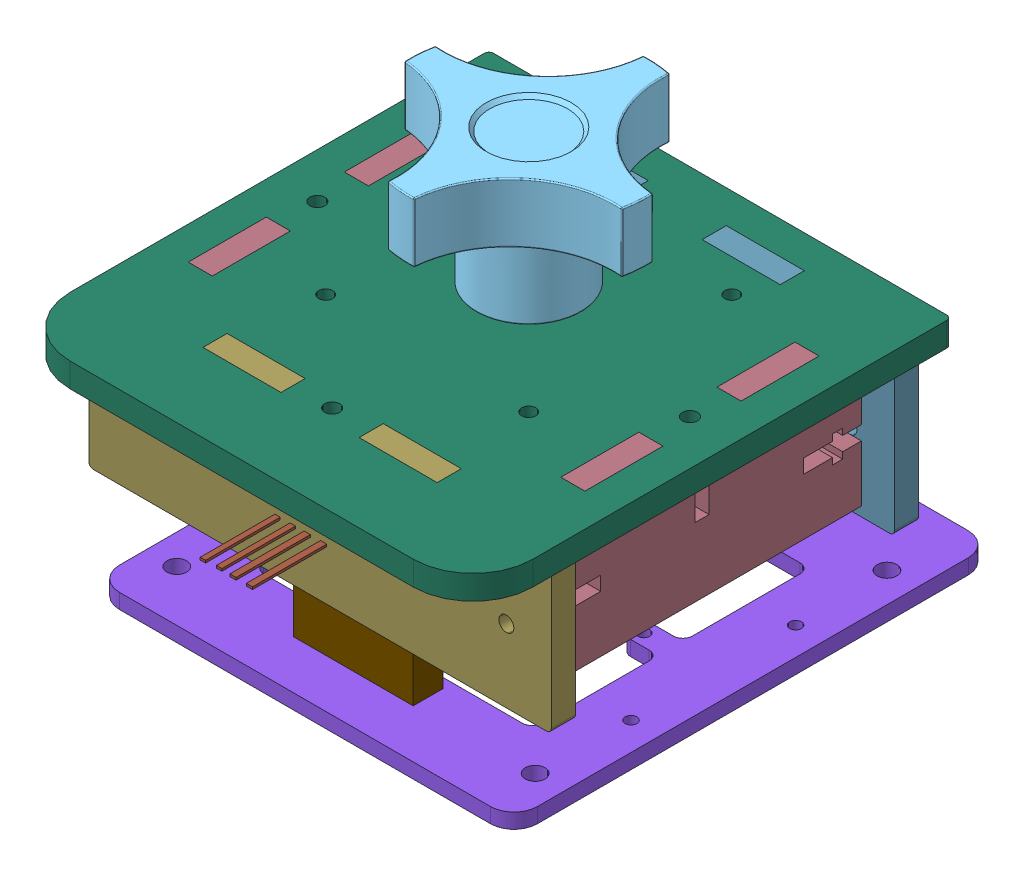
SolidWorks assembly New hinged lid, configuration Default. Lengths in mm.
Overall size (98.36 87.94 115.03).
43 component instances, 23 part files, 83 mates.
Components (placement in the parent):
- Hinge-1: Hinge [Default] at (70.0982 -3.9311 -32.9531) x (-1 0 -0.00001) z (0 -1 -0.000186) size (43.09 12.7 36.52) (hidden)
- Hinge-2: Hinge [Default] at (-25.8646 -55.4891 -84.4606) x (1 0 0.00001) z (-0.00001 0 1) size (43.09 12.7 36.52)
- Hinge bracket-1: Hinge bracket [Default] at (23.7148 -45.0072 -57.9232) x (-0.00001 0 1) z (-1 0 -0.00001) size (19.05 15.24 42.86)
- Heated bracket-1: Heated bracket [Default] at (29.9601 -15.1388 -28.7536) x (1 0 0.00001) z (-0.00001 0.000244 1) size (69.85 3.17 41.91)
- Plate-1: Plate [Default] at (40.7551 -19.901 -27.7973) x (1 0 0.00001) z (-0.00001 0.000244 1) size (48.26 1.59 40)
- compresed spring  9657K81-1: compresed spring  9657K81 [Default] at (-6.4585 -16.615 -30.525) x (0.523814 -0.009189 -0.851783) z (0.851833 0.005651 0.523784) size (5.56 9.65 5.56) (hidden)
- compresed spring  9657K81-3: compresed spring  9657K81 [Default] at (-7.0933 -15.1175 -46.5641) x (-0.445855 -0.000219 -0.895105) z (-0.895105 0.000109 0.445855) size (5.56 9.65 5.56)
- 1-8 in spacer-2: 1-8 in spacer [Default] at (43.7064 -18.3099 -12.9078) x (0.998444 -0.000014 -0.055766) z (0.055766 0.000244 0.998444) size (4.76 3.17 4.76)
- 1-8 in spacer-1: 1-8 in spacer [Default] at (43.7067 -18.3183 -47.1978) x (0.999061 0.000011 0.043334) z (-0.043334 0.000244 0.999061) size (4.76 3.17 4.76)
- 1-8 in spacer-3: 1-8 in spacer [Default] at (0.5267 -18.3183 -47.1982) x (0.966016 -0.000063 -0.258481) z (0.258481 0.000236 0.966016) size (4.76 3.17 4.76) (hidden)
- 1-8 in spacer-4: 1-8 in spacer [Default] at (0.5264 -18.3099 -12.9083) x (0.632801 -0.000189 -0.774315) z (0.774315 0.000155 0.632801) size (4.76 3.17 4.76)
- Lid bracket-1: Lid bracket [Default] at (57.0412 6.5511 5.8182) x (-0.00001 0.000244 1) z (-1 0 -0.00001) size (57.15 29.21 69.85)
- Mounting plate-1: Mounting plate [Default] at (3.5426 -48.1822 -13.4051) size (88.9 3.17 101.6)
- M3_8mm_SS_screw_91292A112-1: M3_8mm_SS_screw_91292A112 [91292A112] at (0.5267 -11.9058 -47.1998) x (0.999971 0.000002 0.007564) z (0 1 -0.000244) size (5.5 5.5 11.58)
- M3_8mm_SS_screw_91292A112-2: M3_8mm_SS_screw_91292A112 [91292A112] at (0.5264 -11.8974 -12.9098) x (0.999971 0.000002 0.007564) z (0 1 -0.000244) size (5.5 5.5 11.58)
- M3_8mm_SS_screw_91292A112-3: M3_8mm_SS_screw_91292A112 [91292A112] at (43.7067 -11.9058 -47.1994) x (0.999971 0.000002 0.007564) z (0 1 -0.000244) size (5.5 5.5 11.58)
- M3_8mm_SS_screw_91292A112-4: M3_8mm_SS_screw_91292A112 [91292A112] at (43.7064 -11.8974 -12.9094) x (0.999971 0.000002 0.007564) z (0 1 -0.000244) size (5.5 5.5 11.58)
- 3-4in-shoulder screw 3-16 dia-1: 3-4in-shoulder screw 3-16 dia [95446A360] at (-7.0933 -24.7938 -46.5617) x (0.905744 -0.000104 -0.423825) z (-0.423825 -0.000221 -0.905744) size (7.94 28.12 7.94)
- 3-4in-shoulder screw 3-16 dia-2: 3-4in-shoulder screw 3-16 dia [95446A360] at (51.3264 -24.7857 -13.5412) x (0.940326 0.000083 0.340275) z (0.340275 -0.00023 -0.940326) size (7.94 28.12 7.94)
- 3-4in-shoulder screw 3-16 dia-3: 3-4in-shoulder screw 3-16 dia [95446A360] at (-7.0936 -24.7857 -13.5417) x (0.940326 0.000083 0.340275) z (0.340275 -0.00023 -0.940326) size (7.94 28.12 7.94)
- 3-4in-shoulder screw 3-16 dia-4: 3-4in-shoulder screw 3-16 dia [95446A360] at (51.3267 -24.7938 -46.5612) x (0.992625 0.00003 0.121222) z (0.121222 -0.000242 -0.992625) size (7.94 28.12 7.94)
- Kapton Heater-1: Kapton Heater [Default] at (26.8423 -18.319 -50.039) x (0.00001 -0.000244 -1) z (1 0 0.00001) size (79.75 1 35)
- Lid_front_wood-1: Lid_front_wood [Default] at (27.0323 -16.8764 9.1767) x (1 0 0.00001) z (-0.00001 0.000244 1) size (98.36 34.13 5.13)
- Lid_side_wood-1: Lid_side_wood [Default] at (59.1667 -23.1699 -43.3132) x (1 0 0.00001) z (-0.00001 0.000244 1) size (5.13 32.13 67.82)
- Lid_side_wood-2: Lid_side_wood [Default] at (-20.0633 -23.1699 -43.314) x (1 0 0.00001) z (-0.00001 0.000244 1) size (5.13 32.13 67.82)
- Lid_back_wood-1: Lid_back_wood [Default] at (14.808 -29.7535 -58.6303) x (-1 0 -0.00001) z (0.00001 -0.000244 -1) size (98.36 34.13 5.13)
- Lid_top_wood-1: Lid_top_wood [Default] at (55.5466 0.6138 -15.6234) x (1 0 0.00001) z (-0.00001 0.000244 1) size (98.36 5.13 101.72)
- M3_8mm_SS_screw_91292A112-5: M3_8mm_SS_screw_91292A112 [91292A112] at (44.4304 -2.0428 15.0076) x (0.999989 -0.004771 0.000006) z (-0.004771 -0.999988 0.001283) size (5.5 5.5 11.58) (suppressed, hidden)
- M3_8mm_SS_screw_91292A112-6: M3_8mm_SS_screw_91292A112 [91292A112] at (44.4304 -2.0941 -24.9924) x (0.999989 -0.004771 0.000006) z (-0.004771 -0.999988 0.001283) size (5.5 5.5 11.58) (suppressed, hidden)
- M3_8mm_SS_screw_91292A112-7: M3_8mm_SS_screw_91292A112 [91292A112] at (-2.3818 -1.8411 -1.9191) x (0.999989 -0.004771 0.000006) z (-0.004771 -0.999988 0.001283) size (5.5 5.5 11.58) (suppressed, hidden)
- M3_8mm_SS_screw_91292A112-8: M3_8mm_SS_screw_91292A112 [91292A112] at (-5.5685 -1.8555 -24.9927) x (0.999989 -0.004771 0.000006) z (-0.004771 -0.999988 0.001283) size (5.5 5.5 11.58) (suppressed, hidden)
- Hinge1-1: Hinge1 [Default] at (27.453 -24.3489 -71.4953) x (-1 0 -0.00001) z (0.00001 0 -1) (suppressed, hidden)
- 5-16in-phlps-black-91249A190-6: 5-16in-phlps-black-91249A190 [91249A190] at (37.9918 -10.3177 -54.6611) x (-1 0 -0.00001) z (0.00001 -0.000244 -1) size (8.18 8.18 10.99)
- 1in-8-32-phlp-91249A201-1: 1in-8-32-phlp-91249A201 [91249A201] at (37.992 -51.1985 -78.0736) x (-0.619923 0 0.784662) z (0 1 0) size (8.18 8.18 28.47)
- 1in-8-32-phlp-91249A201-2: 1in-8-32-phlp-91249A201 [91249A201] at (6.242 -51.1985 -78.0739) x (-0.837169 0 -0.546944) z (0 1 0) size (8.18 8.18 28.47)
- 5-16in-phlps-black-91249A190-7: 5-16in-phlps-black-91249A190 [91249A190] at (6.2418 -10.3177 -54.6614) x (-1 0 -0.00001) z (0.00001 -0.000244 -1) size (8.18 8.18 10.99)
- latch_bracket_2-1: latch_bracket_2 [Default] at (43.6698 -45.0072 13.4302) size (25.4 15.24 6.35)
- latch_2-1: latch_2 [Default] at (43.8409 -12.4473 -1.4793) x (1 -0.000024 0.00001) z (-0.000024 -1 0.000244) size (42.86 9.42 7.94)
- strike_1-1: strike_1 [Default] at (22.836 -29.6346 7.4002) x (-0.000088 0 -1) z (1 0 -0.000088) size (6.75 9.4 25)
- 3-4in-6-32-phlp-undercut-91099A224-1: 3-4in-6-32-phlp-undercut-91099A224 [91099A224] at (14.5756 -29.7616 4.0262) x (1 0 0) z (0 1 0) size (6.65 6.65 19.05)
- 3-4in-6-32-phlp-undercut-91099A224-3: 3-4in-6-32-phlp-undercut-91099A224 [91099A224] at (29.6568 -29.7616 4.0262) x (1 0 0) z (0 1 0) size (6.65 6.65 19.05)
- 1.4inbolt-1: 1.4inbolt [92240A430] at (22.1165 -11.6784 -30.0547) x (0.999158 0.00001 0.041024) z (0 -1 0.000244) size (13.41 13.11 36.14)
- Bolt with knob-1: Bolt with knob [5993K44] at (22.1165 15.9441 -30.0614) x (0.996738 0.00002 0.0807) z (0 1 -0.000244) size (50.8 61.06 29.44)
Mates (geometry in assembly coordinates):
- Concentric38: concentric aligned: circle of Plate-1; circle of 1-8 in spacer-2
- Concentric39: concentric aligned: circle of Plate-1; circle of 1-8 in spacer-4
- Concentric40: concentric aligned: circle of Plate-1; circle of 1-8 in spacer-3
- Coincident53: coincident anti-aligned: plane of Heated bracket-1 through (-12.8087 -15.134 -9.0992) normal (0 -1 0.000244); circle of 1-8 in spacer-4
- Coincident54: coincident anti-aligned: plane of Heated bracket-1 through (-12.8087 -15.134 -9.0992) normal (0 -1 0.000244); circle of 1-8 in spacer-1
- Concentric42: concentric aligned: circle of Plate-1; circle of 1-8 in spacer-1
- Coincident55: coincident anti-aligned: plane of Heated bracket-1 through (-12.8087 -15.134 -9.0992) normal (0 -1 0.000244); plane of 1-8 in spacer-2 through (43.7064 -15.1349 -12.9086) normal (0 1 -0.000244)
- Coincident56: coincident anti-aligned: plane of Heated bracket-1 through (-12.8087 -15.134 -9.0992) normal (0 -1 0.000244); circle of 1-8 in spacer-3
- Coincident80: coincident anti-aligned: plane of Hinge bracket-1 through (43.5483 -45.0072 -83.6616) normal (0 -1 0); plane of Mounting plate-1 through (61.567 -45.0072 -79.0734) normal (0 1 0)
- Concentric43: concentric anti-aligned: circle of Hinge bracket-1; circle of Mounting plate-1
- Coincident91: coincident anti-aligned: plane of Plate-1 through (-2.0137 -18.3092 -10.0533) normal (0 1 -0.000244); plane of 1-8 in spacer-1 through (43.7067 -18.3183 -47.1978) normal (0 -1 0.000244)
- Concentric56: concentric aligned: circle of 1-8 in spacer-3; circle of M3_8mm_SS_screw_91292A112-1
- Concentric57: concentric aligned: circle of Plate-1; circle of M3_8mm_SS_screw_91292A112-1
- Concentric58: concentric anti-aligned: circle of Heated bracket-1; circle of M3_8mm_SS_screw_91292A112-1
- Coincident94: coincident anti-aligned: plane of Plate-1 through (-2.0137 -19.8967 -10.0529) normal (0 -1 0.000244); plane of M3_8mm_SS_screw_91292A112-1 through (0.5267 -19.9058 -47.1979) normal (0 1 -0.000244)
- Concentric60: concentric aligned: circle of 1-8 in spacer-4; circle of M3_8mm_SS_screw_91292A112-2
- Concentric61: concentric aligned: circle of Heated bracket-1; circle of M3_8mm_SS_screw_91292A112-2
- Concentric64: concentric aligned: circle of Plate-1; circle of M3_8mm_SS_screw_91292A112-3
- Concentric65: concentric aligned: circle of Plate-1; circle of M3_8mm_SS_screw_91292A112-4
- Coincident98: coincident anti-aligned: plane of Plate-1 through (-2.0137 -19.8967 -10.0529) normal (0 -1 0.000244); plane of M3_8mm_SS_screw_91292A112-4 through (43.7064 -19.8974 -12.9074) normal (0 1 -0.000244)
- Coincident99: coincident anti-aligned: plane of Plate-1 through (-2.0137 -19.8967 -10.0529) normal (0 -1 0.000244); plane of M3_8mm_SS_screw_91292A112-3 through (43.7067 -19.9058 -47.1974) normal (0 1 -0.000244)
- Coincident100: coincident anti-aligned: plane of Plate-1 through (-2.0137 -19.8967 -10.0529) normal (0 -1 0.000244); plane of M3_8mm_SS_screw_91292A112-2 through (0.5264 -19.8974 -12.9079) normal (0 1 -0.000244)
- Concentric67: concentric anti-aligned: line of Hinge bracket-1 through (37.992 -21.6195 -78.0736) axis (0 -1 0); circle of Mounting plate-1
- Concentric70: concentric anti-aligned: circle of 3-4in-shoulder screw 3-16 dia-2; circle of Lid bracket-1
- Coincident102: coincident anti-aligned: plane of Lid bracket-1 through (-12.8083 -5.7449 -51.0114) normal (0 -1 0.000244); plane of 3-4in-shoulder screw 3-16 dia-2 through (51.3264 -5.7357 -13.5458) normal (0 1 -0.000244)
- Concentric71: concentric anti-aligned: cylinder of 3-4in-shoulder screw 3-16 dia-2 through (51.3264 -5.7357 -13.5458) axis (0 -1 0.000244) radius 2.3813; circle of Heated bracket-1
- Coincident105: coincident aligned: line of Plate-1 through (-2.0137 -18.3092 -10.0533) axis (1 0 0.00001); line of Kapton Heater-1 through (4.825 -18.3092 -10.0532) axis (1 0 0.00001)
- Parallel1: parallel aligned: line of Plate-1 through (-2.0133 -18.319 -50.0533) axis (-0.00001 0.000244 1); line of Kapton Heater-1 through (4.8253 -17.8188 -49.5533) axis (-0.00001 0.000244 1)
- Concentric74: concentric anti-aligned: circle of Mounting plate-1; circle of Hinge-2
- Concentric75: concentric aligned: circle of Mounting plate-1; circle of Hinge-2
- Coincident114: coincident anti-aligned: plane of Hinge bracket-1 through (43.5483 -29.7672 -83.6616) normal (0 1 0); plane of Hinge-2 through (43.8546 -29.7672 -83.9231) normal (0 -1 0)
- Coincident155: coincident anti-aligned: plane of Lid bracket-1 through (-12.8083 -5.7449 -51.0114) normal (0 -1 0.000244); plane of 3-4in-shoulder screw 3-16 dia-1 through (-7.0933 -5.7438 -46.5664) normal (0 1 -0.000244)
- Concentric89: concentric anti-aligned: circle of compresed spring  9657K81-3; circle of 3-4in-shoulder screw 3-16 dia-1
- Coincident166: coincident anti-aligned: plane of Hinge bracket-1 through (43.5483 -29.7672 -83.6616) normal (0 1 0); plane of ? through (44.3421 -29.7672 -85.7726) normal (0 -1 0)
- Coincident168: coincident anti-aligned: plane of Lid bracket-1 through (-12.8082 0.6033 -58.633) normal (0.00001 -0.000244 -1); plane of ? through (-0.1082 -2.6196 -58.6321) normal (-0.00001 0.000244 1)
- Coincident174: coincident anti-aligned: plane of ? through (44.3418 -16.3661 -62.5971) normal (0.00001 -0.000244 -1); plane of 5-16in-phlps-black-91249A190-6 through (37.9918 -10.3197 -62.5986) normal (-0.00001 0.000244 1)
- Coincident175: coincident anti-aligned: plane of ? through (44.3418 -16.3661 -62.5971) normal (0.00001 -0.000244 -1); plane of 5-16in-phlps-black-91249A190-6 through (37.9918 -10.3197 -62.5986) normal (-0.00001 0.000244 1)
- Concentric104: concentric anti-aligned: circle of Mounting plate-1; circle of ?
- Concentric107: concentric anti-aligned: circle of Mounting plate-1; circle of ?
- Concentric108: concentric anti-aligned: circle of ?; circle of 1in-8-32-phlp-91249A201-1
- Concentric109: concentric anti-aligned: circle of ?; circle of 1in-8-32-phlp-91249A201-2
- Coincident177: coincident anti-aligned: plane of ? through (-0.1081 -25.7985 -72.0276) normal (0 1 0); plane of 1in-8-32-phlp-91249A201-1 through (37.992 -25.7985 -78.0736) normal (0 -1 0)
- Coincident178: coincident anti-aligned: plane of ? through (-0.1081 -25.7985 -72.0276) normal (0 1 0); plane of 1in-8-32-phlp-91249A201-2 through (6.242 -25.7985 -78.0739) normal (0 -1 0)
- Concentric110: concentric aligned: circle of Mounting plate-1; circle of latch_bracket_2-1
- Concentric111: concentric aligned: circle of Mounting plate-1; circle of latch_bracket_2-1
- Coincident179: coincident anti-aligned: plane of Mounting plate-1 through (61.567 -45.0072 -79.0734) normal (0 1 0); plane of latch_bracket_2-1 through (9.4162 -45.0072 7.2012) normal (0 -1 0)
- Concentric112: concentric aligned: circle of latch_bracket_2-1; circle of strike_1-1
- Concentric113: concentric aligned: circle of latch_bracket_2-1; circle of strike_1-1
- Coincident180: coincident anti-aligned: plane of latch_bracket_2-1 through (9.4162 -29.7672 7.2012) normal (0 1 0); plane of strike_1-1 through (34.6175 -29.7672 0.6523) normal (0 -1 0)
- Coincident181: coincident anti-aligned: plane of Lid bracket-1 through (-12.8088 -28.5928 -1.4759) normal (-0.00001 0.000244 1); plane of latch_2-1 through (0.6849 -27.7346 -1.4759) normal (0.00001 -0.000244 -1)
- Concentric114: concentric aligned: circle of Lid bracket-1; circle of latch_2-1
- Concentric115: concentric aligned: circle of Lid bracket-1; circle of latch_2-1
- Concentric116: concentric anti-aligned: circle of Lid bracket-1; circle of 3-4in-shoulder screw 3-16 dia-1
- Concentric117: concentric anti-aligned: circle of Heated bracket-1; cylinder of 3-4in-shoulder screw 3-16 dia-1 through (-7.0933 -5.7438 -46.5664) axis (0 -1 0.000244) radius 2.3813
- Concentric118: concentric anti-aligned: circle of Lid bracket-1; circle of 3-4in-shoulder screw 3-16 dia-4
- Concentric119: concentric anti-aligned: circle of Heated bracket-1; cylinder of 3-4in-shoulder screw 3-16 dia-4 through (51.3267 -5.7438 -46.5658) axis (0 -1 0.000244) radius 2.3813
- Coincident182: coincident anti-aligned: plane of Lid bracket-1 through (-12.8083 -5.7449 -51.0114) normal (0 -1 0.000244); plane of 3-4in-shoulder screw 3-16 dia-4 through (51.3267 -5.7438 -46.5658) normal (0 1 -0.000244)
- Concentric120: concentric anti-aligned: circle of Heated bracket-1; cylinder of 3-4in-shoulder screw 3-16 dia-3 through (-7.0936 -5.7357 -13.5464) axis (0 -1 0.000244) radius 2.3813
- Concentric121: concentric aligned: circle of Lid bracket-1; cylinder of 3-4in-shoulder screw 3-16 dia-3 through (-7.0936 -5.7357 -13.5464) axis (0 -1 0.000244) radius 2.3813
- Coincident183: coincident anti-aligned: plane of Lid bracket-1 through (-12.8083 -5.7449 -51.0114) normal (0 -1 0.000244); plane of 3-4in-shoulder screw 3-16 dia-3 through (-7.0936 -5.7357 -13.5464) normal (0 1 -0.000244)
- Concentric123: concentric anti-aligned: circle of Lid bracket-1; circle of ?
- Concentric124: concentric anti-aligned: circle of Lid bracket-1; circle of ?
- Concentric125: concentric anti-aligned: circle of ?; circle of 5-16in-phlps-black-91249A190-6
- Concentric133: concentric anti-aligned: circle of strike_1-1; circle of 3-4in-6-32-phlp-undercut-91099A224-1
- Concentric134: concentric aligned: circle of strike_1-1; circle of 3-4in-6-32-phlp-undercut-91099A224-3
- Coincident186: coincident aligned: cone of strike_1-1 through (14.5756 -28.0146 4.0262) axis (0 -1 0); cone of 3-4in-6-32-phlp-undercut-91099A224-1 through (14.5756 -28.263 4.0262) axis (0 -1 0)
- Coincident187: coincident aligned: cone of strike_1-1 through (29.6568 -28.0146 4.0262) axis (0 -1 0); cone of 3-4in-6-32-phlp-undercut-91099A224-3 through (29.6568 -28.263 4.0262) axis (0 -1 0)
- Coincident188: coincident anti-aligned: plane of Lid bracket-1 through (-12.8088 0.6172 -1.483) normal (0 1 -0.000244); plane of Lid_top_wood-1 through (58.5961 0.6221 18.254) normal (0 -1 0.000244)
- Concentric135: concentric aligned: circle of Lid bracket-1; circle of 1.4inbolt-1
- Concentric136: concentric aligned: circle of 1.4inbolt-1; circle of Bolt with knob-1
- Coincident189: coincident anti-aligned: plane of 1.4inbolt-1 through (22.1165 23.8816 -30.0633) normal (0 1 -0.000244); plane of Bolt with knob-1 through (22.1165 23.8816 -30.0633) normal (0 -1 0.000244)
- Concentric137: concentric aligned: circle of Lid bracket-1; circle of Lid_top_wood-1
- Concentric138: concentric aligned: circle of Lid bracket-1; circle of Lid_top_wood-1
- Coincident191: coincident aligned: line of Lid_back_wood-1 through (-2.7832 5.7333 -58.6392) axis (1 0 0.00001); line of Lid_top_wood-1 through (-2.7832 5.7333 -58.6392) axis (1 0 0.00001)
- Coincident192: coincident aligned: line of Lid_back_wood-1 through (13.8168 5.7333 -58.639) axis (0.00001 -0.000244 -1); line of Lid_top_wood-1 through (13.8168 5.7333 -58.639) axis (0.00001 -0.000244 -1)
- Coincident193: coincident aligned: line of Lid_side_wood-2 through (-20.0633 5.7355 -49.6343) axis (-0.00001 0.000244 1); line of Lid_top_wood-1 through (-20.0633 5.7355 -49.6343) axis (-0.00001 0.000244 1)
- Coincident194: coincident aligned: line of Lid_side_wood-2 through (-14.9333 5.7355 -49.6343) axis (-1 0 -0.00001); line of Lid_top_wood-1 through (-14.9333 5.7355 -49.6343) axis (-1 0 -0.00001)
- Coincident195: coincident aligned: line of Lid_side_wood-1 through (59.1667 5.7355 -49.6336) axis (-0.00001 0.000244 1); line of Lid_top_wood-1 through (59.1667 5.7355 -49.6336) axis (-0.00001 0.000244 1)
- Coincident196: coincident aligned: line of Lid_side_wood-1 through (59.1666 5.7395 -33.0336) axis (1 0 0.00001); line of Lid_top_wood-1 through (59.1666 5.7395 -33.0336) axis (1 0 0.00001)
- Coincident197: coincident aligned: line of Lid_front_wood-1 through (-2.7839 5.7511 14.3008) axis (1 0 0.00001); line of Lid_top_wood-1 through (-2.7839 5.7511 14.3008) axis (1 0 0.00001)
- Coincident198: coincident aligned: line of Lid_front_wood-1 through (13.8161 5.7511 14.301) axis (0.00001 -0.000244 -1); line of Lid_top_wood-1 through (13.8161 5.7511 14.301) axis (0.00001 -0.000244 -1)
- Concentric139: concentric aligned: circle of Lid bracket-1; circle of 5-16in-phlps-black-91249A190-7
- Coincident200: coincident anti-aligned: plane of ? through (44.3418 -16.3661 -62.5971) normal (0.00001 -0.000244 -1); plane of 5-16in-phlps-black-91249A190-7 through (6.2418 -10.3197 -62.5989) normal (-0.00001 0.000244 1)
